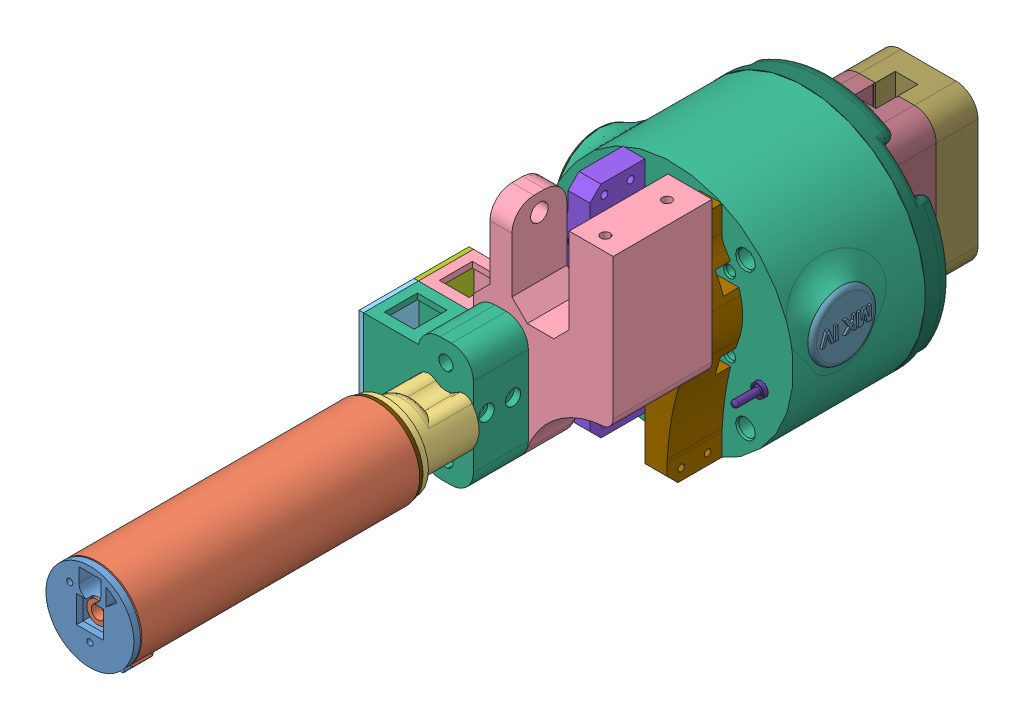
SolidWorks assembly collective_base, configuration По умолчанию. Lengths in mm.
Overall size (116.55 141.43 392.73).
33 component instances, 25 part files, 71 mates.
Components (placement in the parent):
- collective_base_lever_connector_cbase010-1: collective_base_lever_connector_cbase010 [По умолчанию] at (44.3103 52.5722 -4.4772) size (25 25 86)
- 608_bearing_v1-1: 608_bearing_v1 [По умолчанию] at (58.4103 52.5722 5.5228) x (0 -0.975622 0.219457) z (0 0.219457 0.975622) size (22 7.15 22)
- 608_bearing_v1-2: 608_bearing_v1 [По умолчанию] at (16.3103 52.5722 5.5228) x (0 -1 0) z (0 0 1) size (22 7.15 22)
- 608_bearing_v1-3: 608_bearing_v1 [По умолчанию] at (72.3103 52.5722 5.5228) x (0 1 0) z (0 0 1) size (22 7.15 22)
- 608_bearing_v1-4: 608_bearing_v1 [По умолчанию] at (30.2103 52.5722 5.5228) x (0 1 0) z (0 0 1) size (22 7.15 22)
- M8 washer_regular-1: M8 washer_regular [По умолчанию] at (31.8103 52.5722 5.5228) x (0 0 1) z (-1 0 0) size (15.8 15.8 1.5)
- M8 washer_regular-2: M8 washer_regular [По умолчанию] at (58.3103 52.5722 5.5228) x (0 0 1) z (-1 0 0) size (15.8 15.8 1.5)
- collective_base_hinge_frame_p1_cbase007-3: collective_base_hinge_frame_p1_cbase007 [По умолчанию] at (44.3103 52.5722 20.5228) x (1 0 0) z (0 1 0) size (78.5 15 68)
- M6x70mm-1: M6x70mm [По умолчанию] at (5.4103 52.5722 5.5228) x (0 -0.980406 -0.196989) z (0 -0.196989 0.980406) size (11.6 74.3 11.6)
- collective_base_housing_p1_cbase001-1: collective_base_housing_p1_cbase001 [По умолчанию] at (44.3103 44.0722 -32.4772) x (0 1 0) z (1 0 0) size (110 62.47 113.55)
- collective_base_hinge_frame_p2_cbase008-2: collective_base_hinge_frame_p2_cbase008 [По умолчанию] at (44.3103 52.5722 -9.4772) x (-1 0 0) z (0 1 0) size (65 15 68)
- collective_base_friction_tensioner_p2_cbase012-1: collective_base_friction_tensioner_p2_cbase012 [По умолчанию] at (21.8103 44.2222 27.5228) x (1 0 0) z (0 -1 0) size (19.47 25 100)
- collective_base_friction_tensioner_p1_cbase011-1: collective_base_friction_tensioner_p1_cbase011 [По умолчанию] at (66.8103 44.1222 52.5228) x (-1 0 0) z (0 -1 0) size (19.47 25 100)
- 6x6x4mm_square-1: 6x6x4mm_square [По умолчанию] at (2.4103 49.5722 5.5228) size (6 6 4)
- M8 washer_regular-3: M8 washer_regular [По умолчанию] at (72.4103 52.5722 5.5228) x (0 0 -1) z (1 0 0) size (15.8 15.8 1.5)
- M8 washer_regular-4: M8 washer_regular [По умолчанию] at (75.4103 52.5722 5.5228) x (0 0 1) z (-1 0 0) size (15.8 15.8 1.5)
- collective_base_hinge_curtain_cbase009-1: collective_base_hinge_curtain_cbase009 [По умолчанию] at (42.9159 43.7468 -9.4772) x (1 0 0) z (0 0 -1) size (65 54.8 2.4)
- collective_base_housing_p4_cbase004-1: collective_base_housing_p4_cbase004 [По умолчанию] at (44.3103 44.0722 -88.9772) x (-1 0 0) z (0 1 0) size (45 19 69.89)
- collective_base_housing_p3_cbase003-1: collective_base_housing_p3_cbase003 [По умолчанию] at (44.3103 44.0722 -45.4772) x (1 0 0) z (0 1 0) size (45 24.5 69.89)
- collective_base_housing_p6_cbase006-1: collective_base_housing_p6_cbase006 [По умолчанию] at (95.4103 52.0722 6.0228) x (0 0.9998 0.019984) z (0 0.019984 -0.9998) size (32 7 32)
- collective_base_housing_p2_usb_cbase002a-1: collective_base_housing_p2_usb_cbase002a [По умолчанию] at (44.3103 44.0722 -45.4772) x (0 1 0) z (1 0 0) size (110 19.4 110)
- collective_base_housing_p5_cbase005-1: collective_base_housing_p5_cbase005 [По умолчанию] at (-6.7897 54.0722 5.5228) x (0 0.999914 0.013101) z (0 -0.013101 0.999914) size (42 7 42)
- MTS-103-1: MTS-103 [По умолчанию] at (3.9103 30.0722 11.0228) x (0 -1 0) z (-1 0 0) size (13.2 33.3 7.9)
- MTS-103-2: MTS-103 [По умолчанию] at (84.7103 30.0722 11.0228) x (0 1 0) z (1 0 0) size (13.2 33.3 7.9)
- single_collective-1: single_collective [По умолчанию] at (-63.0999 86.8175 -36.0705) x (0 0.95541 -0.295284) z (1 0 0) size (86.99 166.29 46.2)
  - single_throttle_collective_throttle_frame_p1_sthrcl02-1: single_throttle_collective_throttle_frame_p1_sthrcl02 [По умолчанию] at (-107.6719 232.1512 107.4352) x (0.95541 0.295284 0) z (0 0 -1) size (39 92 39)
  - single_throttle_collective_throttle_frame_p2_sthrcl03-1: single_throttle_collective_throttle_frame_p2_sthrcl03 [По умолчанию] at (-112.1012 246.4824 107.4352) x (-0.95541 -0.295284 0) z (0 0 -1) size (40 60 40)
  - single_throttle_collective_throttle_grip_sthrcl04-1: single_throttle_collective_throttle_grip_sthrcl04 [По умолчанию] at (-91.4313 179.6037 107.4352) x (-0.941612 -0.291019 -0.169335) z (-0.295284 0.95541 0) size (40 40 126.4)
  - single_throttle_collective_decorative_casing_sthrcl01-1: single_throttle_collective_decorative_casing_sthrcl01 [По умолчанию] at (-67.218 101.2601 107.4352) x (0.95541 0.295284 0) z (0 0 1) size (38 30 38)
- base_body_connector-3: base_body_connector [Default] at (56.7853 52.5472 105.5228) x (-1 0 0) z (0 -1 0) size (88.55 45.29 101.95)
- body_base_connector_lid-2: body_base_connector_lid [Default] at (9.7853 52.5472 118.0228) x (0 0 -1) z (0 1 0) size (25 5.5 40)
- body_base_connector-2: body_base_connector [Default] at (56.7853 52.5472 105.5228) x (-1 0 0) z (0 1 0) size (50 25 56)
- base_body_connector_lid-2: base_body_connector_lid [Default] at (9.7853 52.5472 93.0228) x (0 0 -1) z (0 1 0) size (25 5.5 40)
Mates (geometry in assembly coordinates):
- Concentric1: concentric anti-aligned: cylinder of collective_base_lever_connector_cbase010-1 through (56.8103 52.5722 5.5228) axis (-1 0 0) radius 3; cylinder of 608_bearing_v1-4 through (26.7353 52.5722 5.5228) axis (1 0 0) radius 4
- Concentric2: concentric anti-aligned: cylinder of 608_bearing_v1-2 through (19.7853 52.5722 5.5228) axis (-1 0 0) radius 4; cylinder of 608_bearing_v1-4 through (26.7353 52.5722 5.5228) axis (1 0 0) radius 4
- Coincident1: coincident anti-aligned: plane of 608_bearing_v1-2 through (23.2603 52.5722 5.5228) normal (1 0 0); plane of 608_bearing_v1-4 through (23.2603 52.5722 5.5228) normal (-1 0 0)
- Concentric3: concentric anti-aligned: cylinder of collective_base_lever_connector_cbase010-1 through (56.8103 52.5722 5.5228) axis (-1 0 0) radius 3; cylinder of 608_bearing_v1-3 through (68.8353 52.5722 5.5228) axis (1 0 0) radius 4
- Concentric4: concentric anti-aligned: cylinder of 608_bearing_v1-1 through (61.8853 52.5722 5.5228) axis (-1 0 0) radius 4; cylinder of 608_bearing_v1-3 through (68.8353 52.5722 5.5228) axis (1 0 0) radius 4
- Coincident2: coincident anti-aligned: plane of 608_bearing_v1-1 through (65.3603 52.5722 5.5228) normal (1 0 0); plane of 608_bearing_v1-3 through (65.3603 52.5722 5.5228) normal (-1 0 0)
- Concentric6: concentric anti-aligned: cylinder of collective_base_lever_connector_cbase010-1 through (56.8103 52.5722 5.5228) axis (-1 0 0) radius 3; cylinder of M8 washer_regular-2 through (56.8103 52.5722 5.5228) axis (1 0 0) radius 4.15
- Coincident5: coincident anti-aligned: plane of collective_base_lever_connector_cbase010-1 through (56.8103 40.0722 80.5228) normal (1 0 0); plane of M8 washer_regular-2 through (56.8103 52.5722 5.5228) normal (-1 0 0)
- Concentric7: concentric anti-aligned: cylinder of collective_base_lever_connector_cbase010-1 through (56.8103 52.5722 5.5228) axis (-1 0 0) radius 3; cylinder of M8 washer_regular-1 through (30.3103 52.5722 5.5228) axis (1 0 0) radius 4.15
- Coincident6: coincident anti-aligned: plane of collective_base_lever_connector_cbase010-1 through (31.8103 40.0722 80.5228) normal (-1 0 0); plane of M8 washer_regular-1 through (31.8103 52.5722 5.5228) normal (1 0 0)
- Coincident7: coincident anti-aligned: plane of 608_bearing_v1-4 through (30.3103 52.5722 5.5228) normal (1 0 0); plane of M8 washer_regular-1 through (30.3103 52.5722 5.5228) normal (-1 0 0)
- Coincident8: coincident anti-aligned: plane of 608_bearing_v1-1 through (58.3103 52.5722 5.5228) normal (-1 0 0); plane of M8 washer_regular-2 through (58.3103 52.5722 5.5228) normal (1 0 0)
- Concentric10: concentric aligned: cylinder of 608_bearing_v1-2 through (19.7853 52.5722 5.5228) axis (-1 0 0) radius 11; cylinder of collective_base_hinge_frame_p1_cbase007-3 through (58.3103 52.5722 5.5228) axis (-1 0 0) radius 11.1
- Coincident9: coincident anti-aligned: plane of 608_bearing_v1-2 through (16.3103 52.5722 5.5228) normal (-1 0 0); plane of collective_base_hinge_frame_p1_cbase007-3 through (16.3103 63.6722 5.5228) normal (1 0 0)
- Angle4: planar angle = 0 rad anti-aligned: plane of collective_base_lever_connector_cbase010-1 through (56.8103 65.0722 80.5228) normal (0 1 0); plane of collective_base_hinge_frame_p1_cbase007-3 through (89.3722 65.3722 11.4363) normal (0 -1 0)
- Concentric14: concentric anti-aligned: cylinder of 608_bearing_v1-3 through (68.8353 52.5722 5.5228) axis (1 0 0) radius 4; cylinder of M6x70mm-1 through (75.4103 52.5722 5.5228) axis (-1 0 0) radius 3
- Parallel1: parallel anti-aligned: plane of collective_base_lever_connector_cbase010-1 through (31.8103 40.0722 80.5228) normal (-1 0 0); plane of collective_base_housing_p1_cbase001-1 through (31.3103 23.4722 27.5228) normal (1 0 0)
- Coincident15: coincident anti-aligned: plane of collective_base_hinge_frame_p1_cbase007-3 through (44.3103 52.5722 20.5228) normal (0 0 1); plane of collective_base_housing_p1_cbase001-1 through (44.3103 44.0722 20.5228) normal (0 0 -1)
- Concentric15: concentric aligned: cylinder of 608_bearing_v1-3 through (68.8353 52.5722 5.5228) axis (1 0 0) radius 11; cylinder of collective_base_hinge_frame_p2_cbase008-2 through (30.3103 52.5722 5.5228) axis (1 0 0) radius 11.1
- Concentric16: concentric anti-aligned: cylinder of collective_base_hinge_frame_p1_cbase007-3 through (18.3103 36.0722 20.5228) axis (0 0 -1) radius 2.15; cylinder of collective_base_hinge_frame_p2_cbase008-2 through (18.3103 36.0722 -9.4772) axis (0 0 1) radius 2.15
- Coincident18: coincident anti-aligned: plane of collective_base_lever_connector_cbase010-1 through (31.8103 40.0722 80.5228) normal (-1 0 0); plane of collective_base_friction_tensioner_p2_cbase012-1 through (31.8103 -5.7778 52.5228) normal (1 0 0)
- Coincident19: coincident anti-aligned: plane of collective_base_housing_p1_cbase001-1 through (44.3103 44.0722 27.5228) normal (0 0 1); plane of collective_base_friction_tensioner_p2_cbase012-1 through (21.8103 44.2222 27.5228) normal (0 0 -1)
- Tangent1: tangent anti-aligned: cylinder of collective_base_housing_p1_cbase001-1 through (26.3103 36.0722 -32.4772) axis (0 0 1) radius 2.25; plane of collective_base_friction_tensioner_p2_cbase012-1 through (29.8103 38.3222 52.5228) normal (0 -1 0)
- Concentric18: concentric aligned: cylinder of collective_base_housing_p1_cbase001-1 through (18.3103 69.0722 -32.4772) axis (0 0 1) radius 2.25; cylinder of collective_base_hinge_frame_p2_cbase008-2 through (18.3103 69.0722 -9.4772) axis (0 0 1) radius 2.15
- Coincident20: coincident anti-aligned: plane of collective_base_housing_p1_cbase001-1 through (44.3103 44.0722 27.5228) normal (0 0 1); plane of collective_base_friction_tensioner_p1_cbase011-1 through (66.8103 44.1222 27.5228) normal (0 0 -1)
- Coincident21: coincident anti-aligned: plane of collective_base_lever_connector_cbase010-1 through (56.8103 40.0722 80.5228) normal (1 0 0); plane of collective_base_friction_tensioner_p1_cbase011-1 through (56.8103 -5.8778 27.5228) normal (-1 0 0)
- Tangent2: tangent anti-aligned: cylinder of collective_base_hinge_frame_p1_cbase007-3 through (62.3103 36.0722 20.5228) axis (0 0 -1) radius 2.15; plane of collective_base_friction_tensioner_p1_cbase011-1 through (58.8103 38.2222 27.5228) normal (0 -1 0)
- Coincident23: coincident anti-aligned: plane of M6x70mm-1 through (5.4103 52.5722 5.5228) normal (-1 0 0); plane of 6x6x4mm_square-1 through (5.4103 55.5722 7.5228) normal (1 0 0)
- Concentric21: concentric anti-aligned: cylinder of M6x70mm-1 through (75.4103 52.5722 5.5228) axis (-1 0 0) radius 3; cylinder of 6x6x4mm_square-1 through (4.4103 52.5722 5.5228) axis (1 0 0) radius 1.5
- Concentric22: concentric anti-aligned: cylinder of M6x70mm-1 through (75.4103 52.5722 5.5228) axis (-1 0 0) radius 3; cylinder of M8 washer_regular-4 through (73.9103 52.5722 5.5228) axis (1 0 0) radius 4.15
- Concentric23: concentric anti-aligned: cylinder of M8 washer_regular-3 through (73.9103 52.5722 5.5228) axis (-1 0 0) radius 4.15; cylinder of M8 washer_regular-4 through (73.9103 52.5722 5.5228) axis (1 0 0) radius 4.15
- Coincident24: coincident anti-aligned: plane of M8 washer_regular-3 through (73.9103 52.5722 5.5228) normal (1 0 0); plane of M8 washer_regular-4 through (73.9103 52.5722 5.5228) normal (-1 0 0)
- Coincident25: coincident anti-aligned: plane of 608_bearing_v1-3 through (72.4103 52.5722 5.5228) normal (1 0 0); plane of M8 washer_regular-3 through (72.4103 52.5722 5.5228) normal (-1 0 0)
- Coincident26: coincident anti-aligned: plane of M6x70mm-1 through (75.4103 52.5722 5.5228) normal (-1 0 0); plane of M8 washer_regular-4 through (75.4103 52.5722 5.5228) normal (1 0 0)
- Concentric28: concentric aligned: cylinder of collective_base_hinge_frame_p2_cbase008-2 through (18.3103 21.0722 -9.4772) axis (0 0 1) radius 2.15; cylinder of collective_base_hinge_curtain_cbase009-1 through (18.3103 21.0722 -11.8772) axis (0 0 1) radius 2.15
- Concentric29: concentric aligned: cylinder of collective_base_hinge_frame_p2_cbase008-2 through (70.3103 21.0722 -9.4772) axis (0 0 1) radius 2.15; cylinder of collective_base_hinge_curtain_cbase009-1 through (70.3103 21.0722 -11.8772) axis (0 0 1) radius 2.15
- Coincident28: coincident anti-aligned: plane of collective_base_hinge_frame_p2_cbase008-2 through (44.3103 52.5722 -9.4772) normal (0 0 -1); plane of collective_base_hinge_curtain_cbase009-1 through (42.9159 43.7468 -9.4772) normal (0 0 1)
- Coincident33: coincident aligned: plane of collective_base_housing_p4_cbase004-1 through (49.4603 13.0722 -69.9772) normal (0 1 0); plane of collective_base_housing_p3_cbase003-1 through (39.1603 13.0722 -69.9772) normal (0 1 0)
- Concentric30: concentric anti-aligned: cylinder of collective_base_housing_p4_cbase004-1 through (59.3103 19.0722 -78.9772) axis (0 0 -1) radius 4.15; cylinder of collective_base_housing_p3_cbase003-1 through (59.3103 19.0722 -59.9772) axis (0 0 1) radius 4.15
- Coincident34: coincident anti-aligned: plane of collective_base_housing_p4_cbase004-1 through (44.3103 44.0722 -69.9772) normal (0 0 1); plane of collective_base_housing_p3_cbase003-1 through (44.3103 44.0722 -69.9772) normal (0 0 -1)
- Concentric40: concentric aligned: cylinder of collective_base_housing_p1_cbase001-1 through (44.3103 44.0722 17.5228) axis (0 0 -1) radius 50; cylinder of collective_base_housing_p2_usb_cbase002a-1 through (44.3103 44.0722 -32.4772) axis (0 0 -1) radius 55
- Concentric41: concentric anti-aligned: cylinder of collective_base_housing_p1_cbase001-1 through (77.5444 10.8382 -32.4772) axis (0 0 1) radius 4; cylinder of collective_base_housing_p2_usb_cbase002a-1 through (77.5444 10.8382 -27.4772) axis (0 0 -1) radius 4.1
- Coincident45: coincident anti-aligned: plane of collective_base_housing_p1_cbase001-1 through (44.3103 44.0722 -32.4772) normal (0 0 -1); plane of collective_base_housing_p2_usb_cbase002a-1 through (44.3103 44.0722 -32.4772) normal (0 0 1)
- Coincident46: coincident anti-aligned: plane of collective_base_housing_p3_cbase003-1 through (44.3103 44.0722 -45.4772) normal (0 0 1); plane of collective_base_housing_p2_usb_cbase002a-1 through (44.3103 44.0722 -45.4772) normal (0 0 -1)
- Concentric42: concentric aligned: cylinder of collective_base_housing_p1_cbase001-1 through (99.3103 52.0722 6.0228) axis (-1 0 0) radius 12.5; cylinder of collective_base_housing_p6_cbase006-1 through (99.4103 52.0722 6.0228) axis (-1 0 0) radius 12.3
- Coincident47: coincident anti-aligned: plane of collective_base_housing_p1_cbase001-1 through (99.4103 52.0722 6.0228) normal (1 0 0); plane of collective_base_housing_p6_cbase006-1 through (99.4103 52.0722 6.0228) normal (-1 0 0)
- Concentric44: concentric anti-aligned: cylinder of collective_base_housing_p1_cbase001-1 through (11.3103 54.0722 5.5228) axis (-1 0 0) radius 17.5; cylinder of collective_base_housing_p5_cbase005-1 through (-10.7897 54.0722 5.5228) axis (1 0 0) radius 17.3
- Coincident48: coincident anti-aligned: plane of collective_base_housing_p1_cbase001-1 through (-10.7897 54.0722 5.5228) normal (-1 0 0); plane of collective_base_housing_p5_cbase005-1 through (-10.7897 54.0722 5.5228) normal (1 0 0)
- Concentric45: concentric aligned: cylinder of collective_base_housing_p1_cbase001-1 through (3.9103 30.0722 29.9925) axis (0 0 -1) radius 3.2; cylinder of MTS-103-1 through (3.9103 30.0722 29.3228) axis (0 0 -1) radius 3
- Concentric46: concentric aligned: cylinder of collective_base_housing_p1_cbase001-1 through (84.7103 30.0722 29.9925) axis (0 0 -1) radius 3.2; cylinder of MTS-103-2 through (84.7103 30.0722 29.3228) axis (0 0 -1) radius 3
- Coincident49: coincident anti-aligned: plane of collective_base_housing_p1_cbase001-1 through (44.3103 44.0722 20.5228) normal (0 0 -1); plane of MTS-103-2 through (84.7103 30.0722 20.5228) normal (0 0 1)
- Parallel2: parallel anti-aligned: plane of collective_base_housing_p1_cbase001-1 through (89.2103 37.0722 -32.4772) normal (-1 0 0); plane of MTS-103-2 through (88.6603 36.6722 20.5228) normal (1 0 0)
- Coincident51: coincident anti-aligned: plane of collective_base_housing_p1_cbase001-1 through (44.3103 44.0722 20.5228) normal (0 0 -1); plane of MTS-103-1 through (3.9103 30.0722 20.5228) normal (0 0 1)
- Parallel3: parallel aligned: plane of collective_base_hinge_frame_p1_cbase007-3 through (11.8103 102.5722 5.5228) normal (-1 0 0); plane of MTS-103-1 through (-0.0397 23.4722 20.5228) normal (-1 0 0)
- Concentric47: concentric aligned: cylinder of collective_base_housing_p4_cbase004-1 through (59.3103 19.0722 -78.9772) axis (0 0 -1) radius 4.15; cylinder of collective_base_housing_p2_usb_cbase002a-1 through (59.3103 19.0722 -27.4772) axis (0 0 -1) radius 4.15
- Concentric49: concentric aligned: cylinder of collective_base_housing_p4_cbase004-1 through (29.3103 19.0722 -78.9772) axis (0 0 -1) radius 4.15; cylinder of collective_base_housing_p2_usb_cbase002a-1 through (29.3103 19.0722 -27.4772) axis (0 0 -1) radius 4.15
- Coincident70: coincident anti-aligned: plane of collective_base_lever_connector_cbase010-1 through (44.3103 52.5722 80.5228) normal (0 0 1); plane of base_body_connector-3 through (56.7853 52.5472 80.5228) normal (0 0 -1)
- Coincident71: coincident aligned: plane of collective_base_lever_connector_cbase010-1 through (49.4353 47.4472 80.5228) normal (0 1 0); plane of base_body_connector-3 through (39.1853 47.4472 119.9478) normal (0 1 0)
- Coincident72: coincident aligned: plane of collective_base_lever_connector_cbase010-1 through (39.1853 47.4472 80.5228) normal (1 0 0); plane of base_body_connector-3 through (39.1853 47.4472 119.9478) normal (1 0 0)
- Coincident73: coincident aligned: plane of base_body_connector-3 through (6.7853 32.5472 80.5228) normal (0 -1 0); plane of body_base_connector-2 through (31.7853 32.5472 130.5228) normal (0 -1 0)
- Coincident74: coincident anti-aligned: plane of base_body_connector-3 through (56.7853 52.5472 105.5228) normal (0 0 1); plane of body_base_connector-2 through (56.7853 52.5472 105.5228) normal (0 0 -1)
- Coincident76: coincident aligned: plane of single_collective-1/single_throttle_collective_decorative_casing_sthrcl01-1 through (49.4853 57.6472 160.5228) normal (0 -1 0); plane of body_base_connector-2 through (39.1853 57.6472 91.0978) normal (0 -1 0)
- Coincident77: coincident aligned: plane of single_collective-1/single_throttle_collective_decorative_casing_sthrcl01-1 through (39.1853 57.6472 160.5228) normal (1 0 0); plane of body_base_connector-2 through (39.1853 57.6472 91.0978) normal (1 0 0)
- Coincident78: coincident anti-aligned: plane of single_collective-1/single_throttle_collective_decorative_casing_sthrcl01-1 through (44.3353 52.4972 130.5228) normal (0 0 -1); plane of body_base_connector-2 through (56.7853 52.5472 130.5228) normal (0 0 1)
- Coincident79: coincident anti-aligned: plane of base_body_connector-3 through (6.7853 72.5472 80.5228) normal (-1 0 0); plane of body_base_connector_lid-2 through (6.7853 52.5472 118.0228) normal (1 0 0)
- Coincident80: coincident aligned: plane of base_body_connector-3 through (6.7853 32.5472 80.5228) normal (0 -1 0); plane of body_base_connector_lid-2 through (4.7853 32.5472 105.5228) normal (0 -1 0)
- Coincident81: coincident aligned: plane of body_base_connector_lid-2 through (4.7853 72.5472 130.5228) normal (0 0 1); plane of body_base_connector-2 through (56.7853 52.5472 130.5228) normal (0 0 1)
- Coincident82: coincident anti-aligned: plane of base_body_connector-3 through (6.7853 72.5472 80.5228) normal (-1 0 0); plane of base_body_connector_lid-2 through (6.7853 52.5472 93.0228) normal (1 0 0)
- Coincident83: coincident aligned: plane of base_body_connector-3 through (6.7853 32.5472 80.5228) normal (0 -1 0); plane of base_body_connector_lid-2 through (4.7853 32.5472 80.5228) normal (0 -1 0)
- Coincident84: coincident aligned: plane of base_body_connector-3 through (56.7853 52.5472 80.5228) normal (0 0 -1); plane of base_body_connector_lid-2 through (4.7853 72.5472 80.5228) normal (0 0 -1)
- Coincident87: coincident: line of base_body_connector-3 through (6.7853 32.5472 80.5228) axis (0 0 1); plane of body_base_connector-2 through (6.7853 32.5472 130.5228) normal (-1 0 0)
